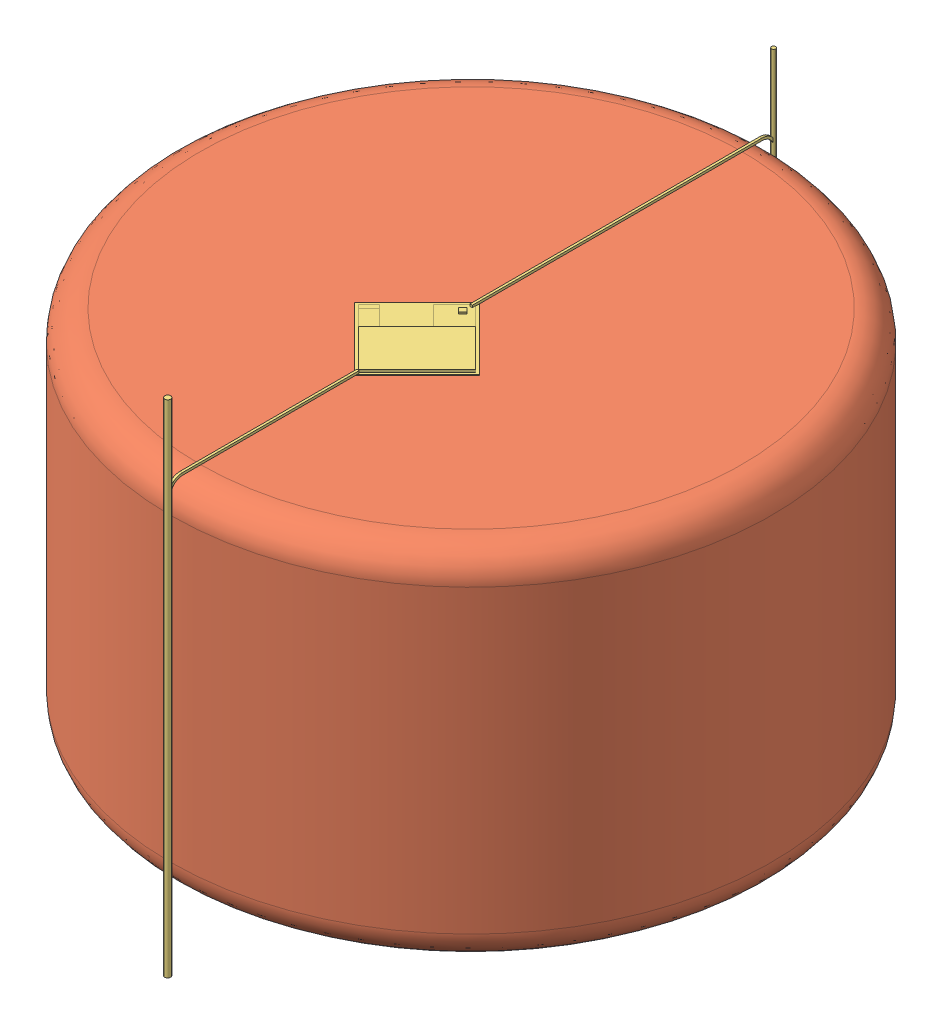
SolidWorks assembly InnerUnit, configuration 默认. Lengths in mm.
Overall size (102 85 103.7).
3 component instances, 3 part files, 4 mates.
Components (placement in the parent):
- BEGeDet-2: BEGeDet [默认] at (1.9481 14.6195 80) x (1 0 0) z (0 0 -1) size (80 40 80)
- InnerShell-3: InnerShell [默认] at (1.9481 -36.3805 80) size (102 61 102)
- Electronics-1: Electronics [默认] at (1.9481 24.7195 80) x (-1 0 0) z (0 0 1) size (21.21 85 103.7)
Mates (geometry in assembly coordinates):
- 重合3: coincident anti-aligned: plane of BEGeDet-2 through (1.9481 14.6195 80) normal (0 1 0); plane of InnerShell-3 through (1.9481 14.6195 80) normal (0 -1 0)
- 同心1: concentric aligned: circle of BEGeDet-2; circle of InnerShell-3
- 重合5: coincident anti-aligned: plane of InnerShell-3 through (1.9481 24.6195 80) normal (0 1 0); plane of Electronics-1 through (1.9481 24.6195 99.799) normal (0 -1 0)
- 同心2: concentric anti-aligned: circle of InnerShell-3; circle of Electronics-1
